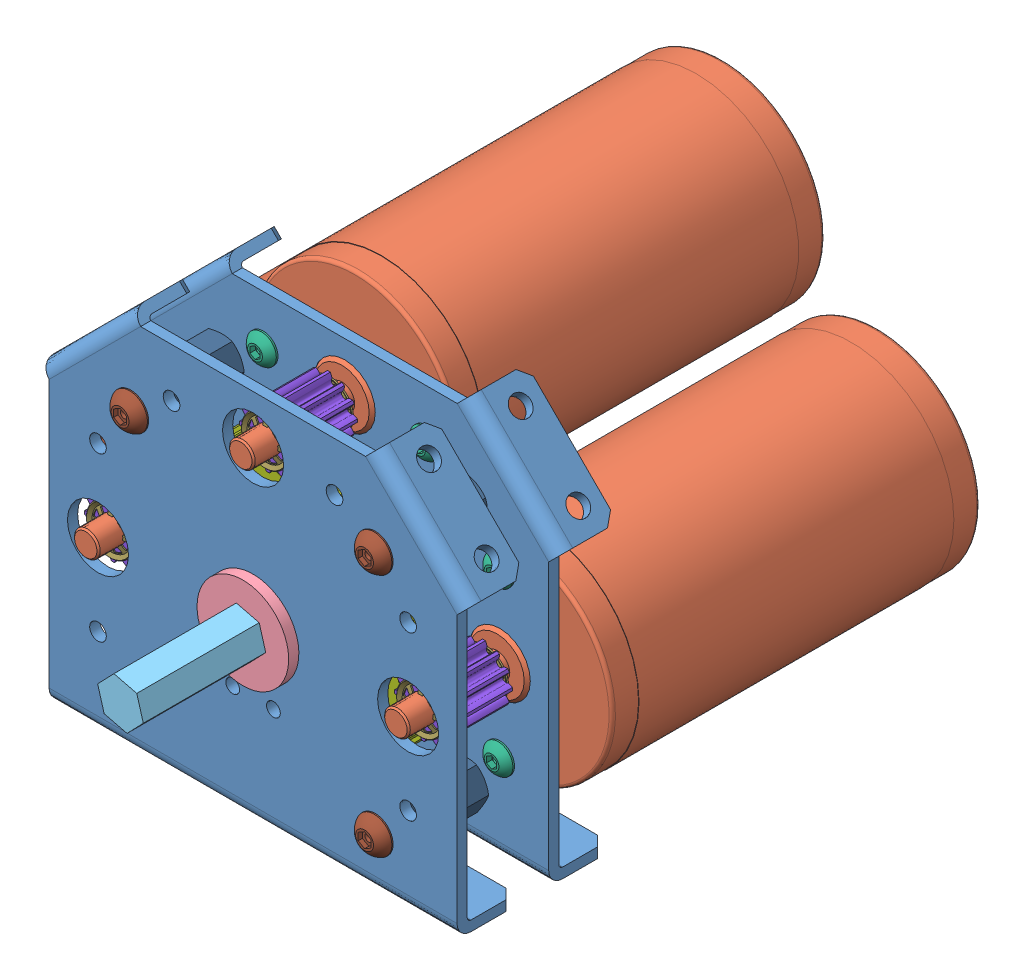
SolidWorks assembly 533 single speed gearbox + motors, configuration Default. Lengths in mm.
Overall size (160.68 132.99 192.44).
44 component instances, 15 part files, 3 mates.
Components (placement in the parent):
- 217-2745-001 Rev1-1: 217-2745-001 Rev1 [Default] at origin size (133.37 119.34 18.42)
- 217-2745-001 Rev1-2: 217-2745-001 Rev1 [Default] at (0 0 28.575) size (133.37 119.34 18.42)
- 217-2000 - CIM Motor-1: 217-2000 - CIM Motor [Default] at (60.96 -35.56 -19.05) x (0 1 0) z (0 0 1) size (64.01 64.01 154.93)
- 217-2000 - CIM Motor-2: 217-2000 - CIM Motor [Default] at (-60.96 35.56 -19.05) x (0 -1 0) z (0 0 1) size (64.01 64.01 154.93)
- 217-2731-1: 217-2731 [Default] at (0 0 -3.175) x (1 0 0) z (0 -1 0) size (31.12 7.94 31.12)
- 217-2734-1: 217-2734 [Default] at (0 0 34.925) x (-0.970869 0.239612 0) z (-0.239612 -0.970869 0) size (31.12 7.94 31.12)
- 217-2454-004 Rev1-1: 217-2454-004 Rev1 [Default] at (0 0 60.3758) x (0 0 1) z (-0.692944 -0.720991 0) size (89.41 12.7 14.66)
- SBS1_SBS1032-0500ZC-1: SBS1_SBS1032-0500ZC [Default] at (-25.4 48.3362 5.7404) x (0 0 -1) z (1 0 0) size (15.78 9.29 9.24)
- 217-2715-001_64t-1: 217-2715-001_64t [Default] at (0 0 20.6629) x (-0.239612 -0.970869 0) z (0 0 1) size (84.3 84.3 12.65)
- 217-2614-001_12t-1: 217-2614-001_12t [Default] at (0 48.3362 17.616) x (0 1 0) z (0 0 1) size (18.29 18.29 19)
- 217-2737 Rev1-1: 217-2737 Rev1 [Default] at (0 0 11.1633) x (0.837918 -0.545796 0) z (0 0 1) size (25.39 25.4 7.82)
- 217-2617-002 Rev1_91780A359-1: 217-2617-002 Rev1_91780A359 [Default] at (38.1 -36.83 15.875) x (0.856767 0.515704 0) z (0 0 1) size (12.7 14.66 25.4)
- SBS1_SBS2520-0500SS-1: SBS1_SBS2520-0500SS [Default] at (38.1 39.37 -3.3528) x (0 0 1) z (-0.923728 -0.383049 0) size (16.73 11.22 11.17)
- 217-2617-002 Rev1_91780A359-2: 217-2617-002 Rev1_91780A359 [Default] at (38.1 39.37 15.875) size (12.7 14.66 25.4)
- 217-2617-002 Rev1_91780A359-3: 217-2617-002 Rev1_91780A359 [Default] at (-38.1 -36.83 15.875) x (0.856767 0.515704 0) z (0 0 1) size (12.7 14.66 25.4)
- 217-2617-002 Rev1_91780A359-4: 217-2617-002 Rev1_91780A359 [Default] at (-38.1 39.37 15.875) x (0.856767 0.515704 0) z (0 0 1) size (12.7 14.66 25.4)
- SBS1_SBS2520-0500SS-2: SBS1_SBS2520-0500SS [Default] at (38.1 39.37 35.1028) x (0 0 -1) z (1 0 0) size (16.73 11.22 11.17)
- SBS1_SBS2520-0500SS-3: SBS1_SBS2520-0500SS [Default] at (-38.1 -36.83 35.1028) x (0 0 -1) z (1 0 0) size (16.73 11.22 11.17)
- SBS1_SBS2520-0500SS-4: SBS1_SBS2520-0500SS [Default] at (-38.1 39.37 35.1028) x (0 0 -1) z (1 0 0) size (16.73 11.22 11.17)
- SBS1_SBS2520-0500SS-5: SBS1_SBS2520-0500SS [Default] at (38.1 -36.83 35.1028) x (0 0 -1) z (1 0 0) size (16.73 11.22 11.17)
- SBS1_SBS2520-0500SS-6: SBS1_SBS2520-0500SS [Default] at (38.1 -36.83 -3.3528) x (0 0 1) z (0.95771 0.287735 0) size (16.73 11.22 11.17)
- SBS1_SBS2520-0500SS-7: SBS1_SBS2520-0500SS [Default] at (-38.1 -36.83 -3.3528) x (0 0 1) z (0.95771 0.287735 0) size (16.73 11.22 11.17)
- SBS1_SBS2520-0500SS-8: SBS1_SBS2520-0500SS [Default] at (-38.1 39.37 -3.3528) x (0 0 1) z (0.95771 0.287735 0) size (16.73 11.22 11.17)
- 217-2614-001_12t-2: 217-2614-001_12t [Default] at (-48.3362 0 17.616) size (18.29 18.29 19)
- 217-2614-001_12t-3: 217-2614-001_12t [Default] at (48.3362 0 17.616) size (18.29 18.29 19)
- 217-2614-002_98430A132-1: 217-2614-002_98430A132 [Default] at (-48.3362 0 27.1156) x (0 0 1) z (-1 0 0) size (1.2 14.83 14.83)
- 217-2614-002_98430A132-2: 217-2614-002_98430A132 [Default] at (-48.3362 0 7.0496) x (0 0 1) z (-1 0 0) size (1.2 14.83 14.83)
- 217-2614-002_98430A132-3: 217-2614-002_98430A132 [Default] at (0 48.3362 27.1156) x (0 0 1) z (-1 0 0) size (1.2 14.83 14.83)
- 217-2614-002_98430A132-4: 217-2614-002_98430A132 [Default] at (0 48.3362 7.0496) x (0 0 1) z (-1 0 0) size (1.2 14.83 14.83)
- 217-2614-002_98430A132-5: 217-2614-002_98430A132 [Default] at (48.3362 0 27.1156) x (0 0 1) z (-1 0 0) size (1.2 14.83 14.83)
- 217-2614-002_98430A132-6: 217-2614-002_98430A132 [Default] at (48.3362 0 7.0496) x (0 0 1) z (-1 0 0) size (1.2 14.83 14.83)
- SBS1_SBS1032-0500ZC-2: SBS1_SBS1032-0500ZC [Default] at (25.4 48.3362 5.7404) x (0 0 -1) z (1 0 0) size (15.78 9.29 9.24)
- SBS1_SBS1032-0500ZC-3: SBS1_SBS1032-0500ZC [Default] at (48.3362 25.4 5.7404) x (0 0 -1) z (1 0 0) size (15.78 9.29 9.24)
- SBS1_SBS1032-0500ZC-4: SBS1_SBS1032-0500ZC [Default] at (48.3362 -25.4 5.7404) x (0 0 -1) z (1 0 0) size (15.78 9.29 9.24)
- SBS1_SBS1032-0500ZC-5: SBS1_SBS1032-0500ZC [Default] at (-48.3362 -25.4 5.7404) x (0 0 -1) z (1 0 0) size (15.78 9.29 9.24)
- SBS1_SBS1032-0500ZC-6: SBS1_SBS1032-0500ZC [Default] at (-48.3362 25.4 5.7404) x (0 0 -1) z (1 0 0) size (15.78 9.29 9.24)
- 217-2745-002 Rev1-1: 217-2745-002 Rev1 [Default] at (0 0 -39.6748) size (25.4 38.1 1.57)
- 217-2428-005 Rev1-1: 217-2428-005 Rev1 [Default] at (6.35 -19.05 -19.05) x (0.995022 0.099653 0) z (-0.099653 0.995022 0) size (7.33 38.98 6.35)
- 217-2428-005 Rev1-2: 217-2428-005 Rev1 [Default] at (-6.35 -19.05 -19.05) x (0.995022 0.099653 0) z (-0.099653 0.995022 0) size (7.33 38.98 6.35)
- SBS1_SBS0832-0500SS-1: SBS1_SBS0832-0500SS [Default] at (-6.35 -19.05 -41.8846) x (0 0 1) z (-1 0 0) size (15.36 8.02 7.99)
- SBS1_SBS0832-0500SS-2: SBS1_SBS0832-0500SS [Default] at (6.35 -19.05 -41.8846) x (0 0 1) z (-1 0 0) size (15.36 8.02 7.99)
- SBS1_SBS0832-0500SS-3: SBS1_SBS0832-0500SS [Default] at (6.35 -19.05 5.3848) x (0 0 -1) z (1 0 0) size (15.36 8.02 7.99)
- SBS1_SBS0832-0500SS-4: SBS1_SBS0832-0500SS [Default] at (-6.35 -19.05 5.3848) x (0 0 -1) z (1 0 0) size (15.36 8.02 7.99)
- 217-2000 - CIM Motor-3: 217-2000 - CIM Motor [Default] at (35.56 157.6324 -19.05) x (-1 0 0) z (0 0 1) size (64.01 64.01 154.93)
Mates (geometry in assembly coordinates):
- Coincident1: coincident anti-aligned: plane of 217-2745-001 Rev1-1 through (63.5762 -48.26 0) normal (0 0 -1); plane of 217-2000 - CIM Motor-2 through (48.3362 -10.5283 0) normal (0 0 1)
- Concentric2: concentric anti-aligned: cylinder of 217-2745-001 Rev1-1 through (48.3362 0 3.175) axis (0 0 -1) radius 9.525; cylinder of 217-2000 - CIM Motor-2 through (48.3362 0 0) axis (0 0 1) radius 9.525
- Concentric5: concentric aligned: cylinder of 217-2745-001 Rev1-2 through (48.3362 25.4 31.75) axis (0 0 -1) radius 2.6035; cylinder of 217-2000 - CIM Motor-2 through (48.3362 25.4 0) axis (0 0 -1) radius 2.0193
